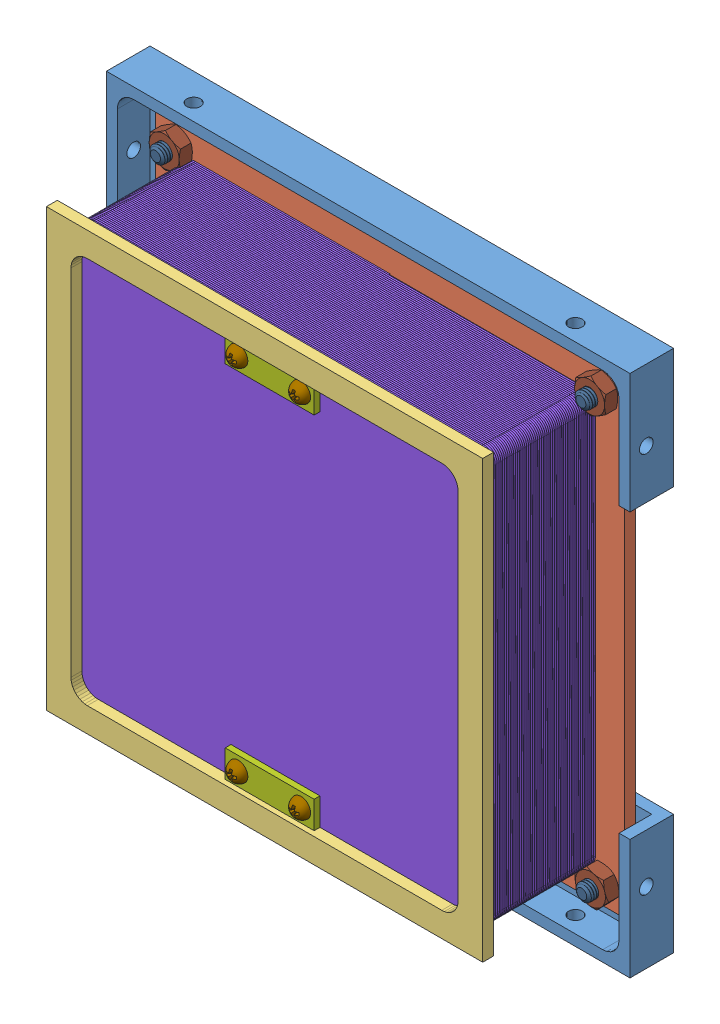
SolidWorks assembly COILS_ASSEMBLY, configuration Default. Lengths in mm.
Overall size (96 96 30.72).
35 component instances, 11 part files, 20 mates.
Components (placement in the parent):
- STANDARD_MOUNTING_BRACKET_COILS-1: STANDARD_MOUNTING_BRACKET_COILS [Default] at (52.6905 12.4661 89.2142) size (96 96 8)
- Full_MT_Assembly-1: Full_MT_Assembly [Default] at (87.0641 56.7594 26.9574) x (-1 0 0) z (0 0 1) size (86 86 25.67)
  - AirCoreBase-2: AirCoreBase [Default] at (-9.6264 88.2933 66.2568) x (1 0 0) z (0 -1 0) size (86 2.09 86)
  - AirCoreSide-2: AirCoreSide [Default] at (-9.6264 88.2933 64.2568) x (1 0 0) z (0 -1 0) size (80 23.15 80)
  - RodHat_v4-2: RodHat_v4 [Default] at (34.3736 13.7933 80.8268) x (1 0 0) z (0 1 0) size (16.31 5.11 5)
  - RodHat_v4-3: RodHat_v4 [Default] at (34.3736 79.7933 80.8268) x (1 0 0) z (0 1 0) size (16.31 5.11 5)
  - RodHat_v4-4: RodHat_v4 [Default] at (64.8736 44.2933 70.7568) x (0 1 0) z (-1 0 0) size (16.31 5.11 5)
  - RodHat_v4-5: RodHat_v4 [Default] at (-1.1263 44.2933 70.7568) x (0 1 0) z (-1 0 0) size (16.31 5.11 5)
  - Rod_Spiral_Assembly-1: Rod_Spiral_Assembly [Default] at (34.3736 8.7933 83.3268) size (8.7 71 7.53)
    - TorqueRod-1: TorqueRod [Default] at origin size (6.73 71 6.73)
    - RodSpiral-1: RodSpiral [Default] at (0 66 0) x (0 0 1) z (0 -1 0) size (7.53 8.7 61.32)
  - Rod_Spiral_Assembly-3: Rod_Spiral_Assembly [Default] at (69.8736 44.2933 73.2568) x (0 0 1) z (0 -1 0) size (8.7 71 7.53)
    - TorqueRod-1: TorqueRod [Default] at origin size (6.73 71 6.73)
    - RodSpiral-1: RodSpiral [Default] at (0 66 0) x (0 0 1) z (0 -1 0) size (7.53 8.7 61.32)
  - RodHatTop-1: RodHatTop [Default] at (34.3736 8.7933 85.8268) x (1 0 0) z (0 -1 0) size (16.31 5 5)
  - RodHatTop-3: RodHatTop [Default] at (3.8737 44.2933 75.7568) x (0 1 0) z (1 0 0) size (16.31 5 5)
  - RodHatTop-4: RodHatTop [Default] at (69.8736 44.2933 75.7568) x (0 1 0) z (1 0 0) size (16.31 5 5)
  - RodHatTop-5: RodHatTop [Default] at (34.3736 79.7933 85.8268) x (-1 0 0) z (0 1 0) size (16.31 5 5)
  - AirCoreSpiral-1: AirCoreSpiral [Default] at (34.3736 44.2933 66.2568) size (75.7 75.86 21.34)
  - round head screw_ai-1: round head screw_ai [CR-RHMS 0.073-72x0.125x0.125-N] at (40.1286 11.2933 89.8762) x (0 0 -1) z (1 0 0) size (4.68 3.51 3.51)
  - round head screw_ai-4: round head screw_ai [CR-RHMS 0.073-72x0.125x0.125-N] at (28.6186 11.2933 89.8762) x (0 0 -1) z (1 0 0) size (4.68 3.51 3.51)
  - round head screw_ai-5: round head screw_ai [CR-RHMS 0.073-72x0.125x0.125-N] at (1.3737 38.5383 79.8062) x (0 0 -1) z (1 0 0) size (4.68 3.51 3.51)
  - round head screw_ai-6: round head screw_ai [CR-RHMS 0.073-72x0.125x0.125-N] at (1.3737 50.0483 79.8062) x (0 0 -1) z (1 0 0) size (4.68 3.51 3.51)
  - round head screw_ai-7: round head screw_ai [CR-RHMS 0.073-72x0.125x0.125-N] at (28.6186 77.2933 89.8762) x (0 0 -1) z (1 0 0) size (4.68 3.51 3.51)
  - round head screw_ai-8: round head screw_ai [CR-RHMS 0.073-72x0.125x0.125-N] at (40.1286 77.2933 89.8762) x (0 0 -1) z (1 0 0) size (4.68 3.51 3.51)
  - round head screw_ai-10: round head screw_ai [CR-RHMS 0.073-72x0.125x0.125-N] at (67.3736 50.0483 79.8062) x (0 0 -1) z (1 0 0) size (4.68 3.51 3.51)
  - round head screw_ai-11: round head screw_ai [CR-RHMS 0.073-72x0.125x0.125-N] at (67.3736 38.5383 79.8062) x (0 0 -1) z (1 0 0) size (4.68 3.51 3.51)
- M3_8mm_SCREW-1: M3_8mm_SCREW [91292A112] at (91.8431 -26.6069 97.2142) x (0.246414 0.969165 0) z (0 0 1) size (5.5 5.5 11.2)
- M3_8mm_SCREW-2: M3_8mm_SCREW [91292A112] at (13.5553 -26.5255 97.2142) x (0.222273 -0.974984 0) z (0 0 1) size (5.5 5.5 11.2)
- M3_8mm_SCREW-3: M3_8mm_SCREW [91292A112] at (13.6905 51.4661 97.2142) x (0.527737 0.849408 0) z (0 0 1) size (5.5 5.5 11.2)
- M3_8mm_SCREW-4: M3_8mm_SCREW [91292A112] at (91.6905 51.4661 97.2142) size (5.5 5.5 11.2)
- M3_NUT-1: M3_NUT [91828A211] at (13.5553 -26.5255 94.4142) size (5.5 6.35 2.78)
- M3_NUT-2: M3_NUT [91828A211] at (91.8431 -26.6069 94.4142) x (0.958223 0.286022 0) z (0 0 1) size (5.5 6.35 2.78)
- M3_NUT-3: M3_NUT [91828A211] at (13.6905 51.4661 94.4142) size (5.5 6.35 2.78)
- M3_NUT-4: M3_NUT [91828A211] at (91.6905 51.4661 94.4142) size (5.5 6.35 2.78)
Mates (geometry in assembly coordinates):
- Concentric4: concentric aligned: circle of STANDARD_MOUNTING_BRACKET_COILS-1; circle of Full_MT_Assembly-1/AirCoreBase-2
- Coincident5: coincident anti-aligned: plane of STANDARD_MOUNTING_BRACKET_COILS-1 through (52.6905 12.4661 91.2142) normal (0 0 1); plane of Full_MT_Assembly-1/AirCoreBase-2 through (96.6905 -31.5339 91.2142) normal (0 0 -1)
- Concentric5: concentric aligned: cylinder of STANDARD_MOUNTING_BRACKET_COILS-1 through (91.6905 51.4661 91.2142) axis (0 0 1) radius 1.25; cylinder of Full_MT_Assembly-1/AirCoreBase-2 through (91.6905 51.4661 93.2142) axis (0 0 1) radius 1.25
- Concentric6: concentric aligned: cylinder of STANDARD_MOUNTING_BRACKET_COILS-1 through (13.6905 51.4661 91.2142) axis (0 0 1) radius 1.25; cylinder of Full_MT_Assembly-1/AirCoreBase-2 through (13.6905 51.4661 93.2142) axis (0 0 1) radius 1.25
- Concentric7: concentric aligned: cylinder of STANDARD_MOUNTING_BRACKET_COILS-1 through (13.6905 -26.5339 91.2142) axis (0 0 1) radius 1.25; cylinder of Full_MT_Assembly-1/AirCoreBase-2 through (13.6905 -26.5339 93.2142) axis (0 0 1) radius 1.25
- Tangent1: tangent: curve of STANDARD_MOUNTING_BRACKET_COILS-1; curve of M3_8mm_SCREW-1
- Coincident6: coincident anti-aligned: plane of STANDARD_MOUNTING_BRACKET_COILS-1 through (52.6905 12.4661 89.2142) normal (0 0 -1); plane of M3_8mm_SCREW-1 through (91.8431 -26.6069 89.2142) normal (0 0 1)
- Concentric8: concentric anti-aligned: cylinder of M3_8mm_SCREW-1 through (91.8431 -26.6069 89.2142) axis (0 0 1) radius 1.5; cylinder of M3_NUT-2 through (91.8431 -26.6069 95.6142) axis (0 0 -1) radius 1.5
- Coincident7: coincident anti-aligned: plane of Full_MT_Assembly-1/AirCoreBase-2 through (96.6905 -31.5339 93.2142) normal (0 0 1); plane of M3_NUT-2 through (88.7539 -25.872 93.2142) normal (0 0 -1)
- Tangent5: tangent: circle of STANDARD_MOUNTING_BRACKET_COILS-1; curve of M3_8mm_SCREW-2
- Coincident9: coincident anti-aligned: plane of STANDARD_MOUNTING_BRACKET_COILS-1 through (52.6905 12.4661 89.2142) normal (0 0 -1); plane of M3_8mm_SCREW-2 through (13.5553 -26.5255 89.2142) normal (0 0 1)
- Concentric9: concentric anti-aligned: cylinder of M3_8mm_SCREW-2 through (13.5553 -26.5255 89.2142) axis (0 0 1) radius 1.5; cylinder of M3_NUT-1 through (13.5553 -26.5255 95.6142) axis (0 0 -1) radius 1.5
- Coincident10: coincident anti-aligned: plane of Full_MT_Assembly-1/AirCoreBase-2 through (96.6905 -31.5339 93.2142) normal (0 0 1); plane of M3_NUT-1 through (10.8053 -24.9378 93.2142) normal (0 0 -1)
- Concentric10: concentric anti-aligned: cylinder of M3_8mm_SCREW-3 through (13.6905 51.4661 89.2142) axis (0 0 1) radius 1.5; cylinder of M3_NUT-3 through (13.6905 51.4661 95.6142) axis (0 0 -1) radius 1.5
- Coincident11: coincident anti-aligned: plane of Full_MT_Assembly-1/AirCoreBase-2 through (96.6905 -31.5339 93.2142) normal (0 0 1); plane of M3_NUT-3 through (10.9405 53.0538 93.2142) normal (0 0 -1)
- Concentric11: concentric anti-aligned: circle of STANDARD_MOUNTING_BRACKET_COILS-1; circle of M3_8mm_SCREW-3
- Concentric12: concentric anti-aligned: circle of STANDARD_MOUNTING_BRACKET_COILS-1; circle of M3_8mm_SCREW-4
- Coincident12: coincident anti-aligned: plane of STANDARD_MOUNTING_BRACKET_COILS-1 through (52.6905 12.4661 89.2142) normal (0 0 -1); plane of M3_8mm_SCREW-4 through (91.6905 51.4661 89.2142) normal (0 0 1)
- Concentric13: concentric anti-aligned: cylinder of M3_8mm_SCREW-4 through (91.6905 51.4661 89.2142) axis (0 0 1) radius 1.5; cylinder of M3_NUT-4 through (91.6905 51.4661 95.6142) axis (0 0 -1) radius 1.5
- Coincident13: coincident anti-aligned: plane of Full_MT_Assembly-1/AirCoreBase-2 through (96.6905 -31.5339 93.2142) normal (0 0 1); plane of M3_NUT-4 through (88.9405 53.0538 93.2142) normal (0 0 -1)
